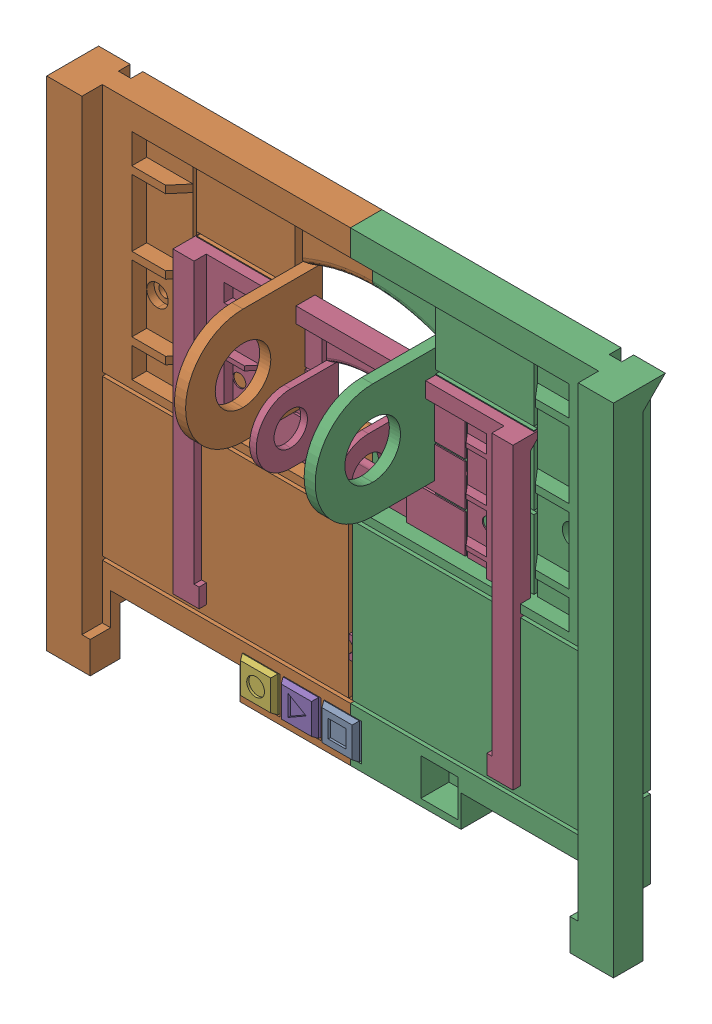
SolidWorks assembly body-top, configuration Default. Lengths in mm.
Overall size (255 224 61.67).
4 component instances, 4 part files, 9 mates.
Components (placement in the parent):
- body-top-stop-button-1: body-top-stop-button [Default] at (-7.9897 -0.5704 4.6035) size (16 16 10)
- body-top-1: body-top [Default] at (-72.862 26.0228 1.6058) x (1 0 0) z (0 -1 0) size (255 61.67 224)
- body-top-play-button-1: body-top-play-button [Default] at (-26.323 -0.5704 4.6035) size (16 16 10)
- body-top-circle-button-1: body-top-circle-button [Default] at (-44.6564 -0.5704 4.6035) size (16 16 10)
Mates (geometry in assembly coordinates):
- Coincident3: coincident anti-aligned: plane of body-top-stop-button-1 through (-7.9897 15.4296 14.6035) normal (0 1 0); plane of body-top-1 through (-7.9897 15.4296 -0.3965) normal (0 -1 0)
- Coincident4: coincident anti-aligned: plane of body-top-stop-button-1 through (-7.9897 -0.5704 14.6035) normal (-1 0 0); plane of body-top-1 through (-7.9897 15.4296 -0.3965) normal (1 0 0)
- Distance1: distance = 5 mm anti-aligned: plane of body-top-stop-button-1 through (-7.9897 -0.5704 4.6035) normal (0 0 -1); plane of body-top-1 through (-72.862 26.0228 -0.3965) normal (0 0 1)
- Coincident6: coincident anti-aligned: plane of body-top-1 through (-26.323 15.4296 -0.3965) normal (0 -1 0); plane of body-top-play-button-1 through (-26.323 15.4296 14.6035) normal (0 1 0)
- Coincident7: coincident anti-aligned: plane of body-top-1 through (-26.323 15.4296 -0.3965) normal (1 0 0); plane of body-top-play-button-1 through (-26.323 -0.5704 14.6035) normal (-1 0 0)
- Distance2: distance = 5 mm anti-aligned: plane of body-top-play-button-1 through (-26.323 -0.5704 4.6035) normal (0 0 -1); plane of body-top-1 through (-72.862 26.0228 -0.3965) normal (0 0 1)
- Coincident9: coincident: plane of body-top-1 through (-44.6564 15.4296 -0.3965) normal (0 -1 0); plane of body-top-circle-button-1 through (-44.6564 15.4296 14.6035) normal (0 1 0)
- Coincident10: coincident: plane of body-top-1 through (-44.6564 15.4296 -0.3965) normal (1 0 0); plane of body-top-circle-button-1 through (-44.6564 -0.5704 14.6035) normal (-1 0 0)
- Distance3: distance = 5 mm anti-aligned: plane of body-top-circle-button-1 through (-44.6564 -0.5704 4.6035) normal (0 0 -1); plane of body-top-1 through (-72.862 26.0228 -0.3965) normal (0 0 1)
